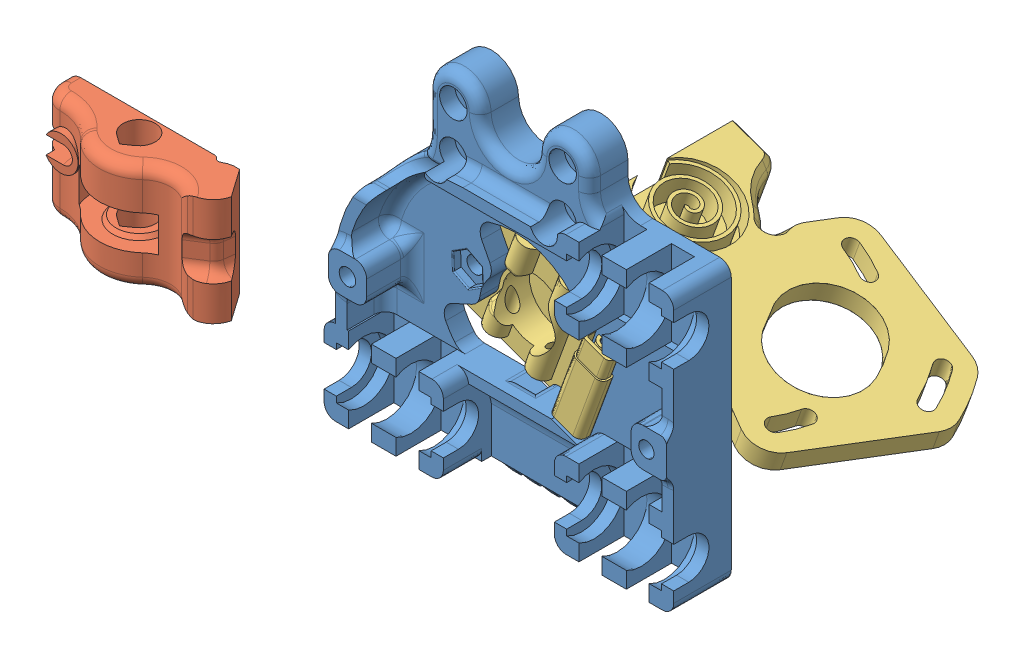
SolidWorks assembly Assembly, configuration Default. Lengths in mm.
Overall size (173.8 91.95 91.58).
3 component instances, 3 part files, 3 mates.
Components (placement in the parent):
- xCarriage_frontbelt-1: xCarriage_frontbelt [Default] at (41.7526 -17.1046 -10.4117) size (91.12 91.95 18.23)
- Eckstruder_Idler-1: Eckstruder_Idler [Default] at (-82.8298 -0.9781 8.0317) size (49.5 28.29 15.92)
- Eckstruder-16mm-insertx1-1: Eckstruder-16mm-insertx1 [Default] at (80.9038 -12.9357 -10.4117) x (-0.939693 0.34202 0) z (-0.34202 -0.939693 0) size (93.48 66.55 28.55)
Mates (geometry in assembly coordinates):
- Coincident1: coincident anti-aligned: plane of xCarriage_frontbelt-1 through (5.2966 -1.3796 -10.4117) normal (0 0 -1); plane of Eckstruder-16mm-insertx1-1 through (80.9038 -12.9357 -10.4117) normal (0 0 1)
- Concentric2: concentric anti-aligned: cylinder of xCarriage_frontbelt-1 through (-6.8528 4.1066 -37.6325) axis (0 0 1) radius 2.15; cylinder of Eckstruder-16mm-insertx1-1 through (-6.8528 4.1066 -10.4117) axis (0 0 -1) radius 2.15
- Parallel1: parallel anti-aligned: plane of xCarriage_frontbelt-1 through (21.4334 -15.8941 -30.3112) normal (-0.939693 0.34202 0); plane of Eckstruder-16mm-insertx1-1 through (21.5172 -15.3712 -10.4117) normal (0.939693 -0.34202 0)
